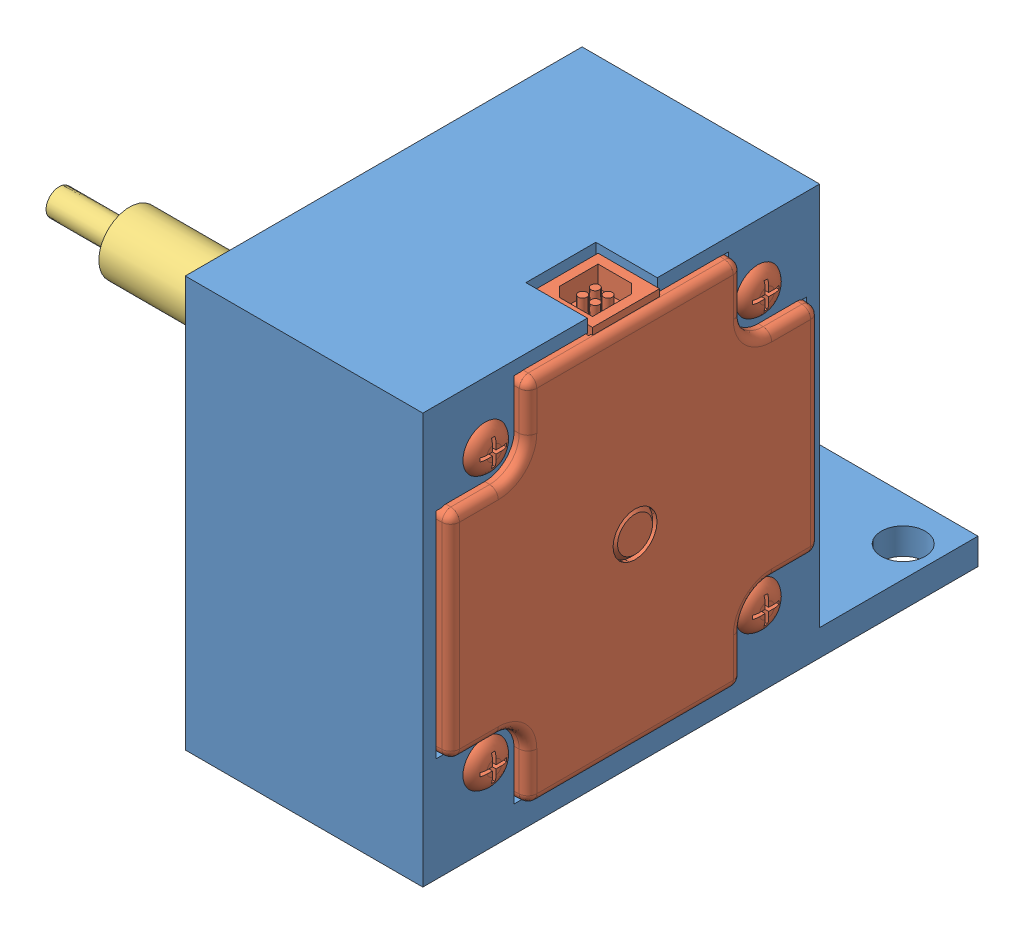
SolidWorks assembly stepper with holder, configuration Default. Lengths in mm.
Overall size (65.45 46.66 63.1).
3 component instances, 3 part files, 6 mates.
Components (placement in the parent):
- z lift stepper holder-1: z lift stepper holder [Default] at origin size (27 46.66 63.1)
- 6627T65_Position-Control DC Motor-1: 6627T65_Position-Control DC Motor [6627T65] at (-1.178 24.209 -22.582) x (0 0 1) z (-1 0 0) size (42.42 42.97 55.75)
- Sleeve motor to gear-1: Sleeve motor to gear [Default] at (-36.91 24.209 -22.582) x (0 -1 0) z (0 0 1) size (7 30 7)
Mates (geometry in assembly coordinates):
- Coincident11: coincident anti-aligned: plane of 6627T65_Position-Control DC Motor-1 through (26 24.209 -22.582) normal (1 0 0); plane of z lift stepper holder-1 through (26 3 0) normal (-1 0 0)
- Coincident12: coincident anti-aligned: plane of z lift stepper holder-1 through (27 0 -1.5) normal (0 0 -1); plane of 6627T65_Position-Control DC Motor-1 through (499998.822 36.6345 -1.5) normal (0 0 1)
- Coincident13: coincident anti-aligned: plane of z lift stepper holder-1 through (27 3 0) normal (0 1 0); plane of 6627T65_Position-Control DC Motor-1 through (6.3912 3 -8.6982) normal (0 -1 0)
- Concentric1: concentric anti-aligned: cylinder of 6627T65_Position-Control DC Motor-1 through (-27.21 24.209 -22.582) axis (-1 0 0) radius 2.5; cylinder of Sleeve motor to gear-1 through (-26.91 24.209 -22.582) axis (1 0 0) radius 2.5
- Concentric2: concentric aligned: circle of 6627T65_Position-Control DC Motor-1; circle of Sleeve motor to gear-1
- Coincident14: coincident anti-aligned: plane of 6627T65_Position-Control DC Motor-1 through (-6.91 27.209 -43.791) normal (-1 0 0); plane of Sleeve motor to gear-1 through (-6.91 24.209 -22.582) normal (1 0 0)
